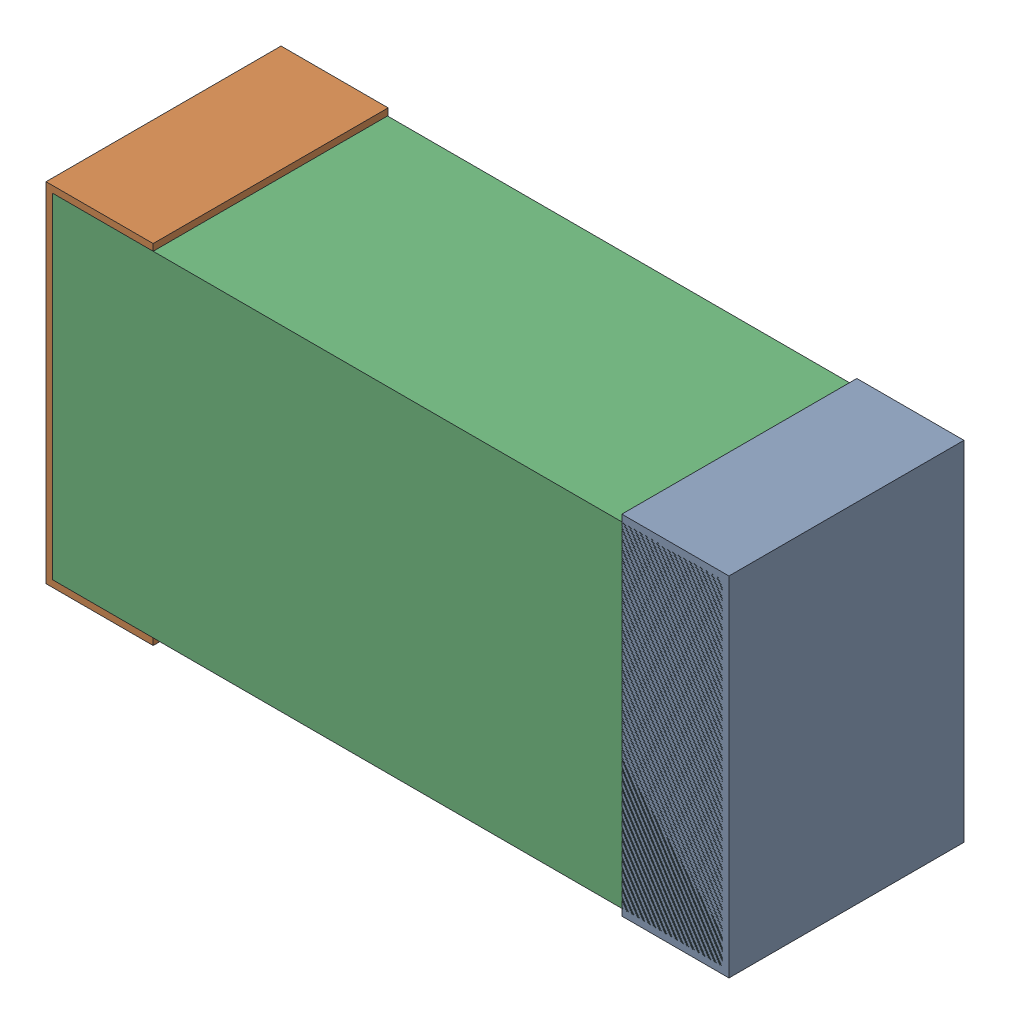
SolidWorks assembly C25, configuration Default. Lengths in mm.
Overall size (1.02 0.52 0.35).
6 component instances, 2 part files, 0 mates.
Components (placement in the parent):
- 870940480-1: 870940480 [Default] at (7.923 33.147 -1.9516) size (0.16 0.52 0.35)
  - Extruded-1: Extruded [Default] at origin size (0.16 0.52 0.35)
- 870940480-2: 870940480 [Default] at (7.063 33.147 -1.9516) size (0.16 0.52 0.35)
  - Extruded-1: Extruded [Default] at origin size (0.16 0.52 0.35)
- 870940640-1: 870940640 [Default] at (7.493 33.147 -1.9506) size (1 0.5 0.35)
  - Extruded_2-1: Extruded_2 [Default] at origin size (1 0.5 0.35)
